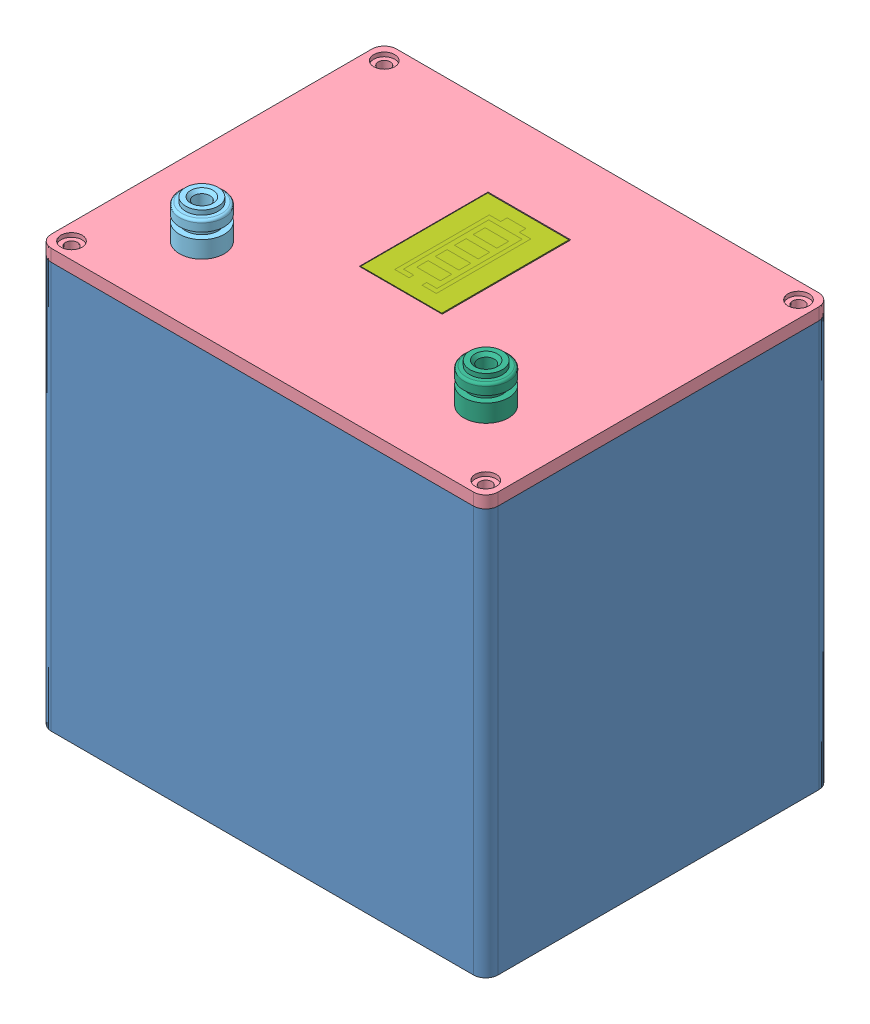
SolidWorks assembly BATTERY_ASSEM, configuration Default. Lengths in mm.
Overall size (110 112.56 85).
7 component instances, 7 part files, 9 mates.
Components (placement in the parent):
- Body-2: Body [Default] at (-59.4434 65 40.4582) size (110 100 85)
- Plate-2: Plate [Default] at (-9.4439 141 3.0418) size (99.4 2 74.4)
- ESP32_WROOM_32D-1: ESP32_WROOM_32D [Default] at (-26.4896 143.4115 23.6321) x (1 0 0) z (0 1 0) size (55 40 12.25)
- Cover-1: Cover [Default] at (-64.4434 160 45.4582) size (110 5.5 85)
- 4mm Black Banana Female Socket Jack Mount Connectors-1: 4mm Black Banana Female Socket Jack Mount Connectors [Default] at (-44.4434 172.4214 25.3582) x (0.999999 0 -0.001164) z (0 -1 0) size (11 17.07 15.05)
- 4mm Red Banana Female Socket Jack Mount Connectors-1: 4mm Red Banana Female Socket Jack Mount Connectors [Default] at (25.5566 172.564 25.3582) x (0.995817 0 -0.09137) z (0 -1 0) size (11 17.07 15.05)
- Lithium Battery Capacity Indicator Module-1: Lithium Battery Capacity Indicator Module [Default] at (-9.4973 157 -4.4242) x (1 0 0) z (0 1 0) size (20 43.5 8)
Mates (geometry in assembly coordinates):
- Coincident1: coincident anti-aligned: plane of Body-2 through (-59.4434 138.5 40.4582) normal (0 -1 0); plane of Plate-1 through (-9.2659 138.5 0.3116) normal (0 1 0)
- Coincident2: coincident anti-aligned: plane of Body-2 through (-59.4434 141 40.4582) normal (0 1 0); plane of Plate-2 through (-9.4439 141 3.0418) normal (0 -1 0)
- Coincident3: coincident anti-aligned: plane of Plate-2 through (-9.4439 143 3.0418) normal (0 1 0); plane of ESP32_WROOM_32D-1 through (1.7713 143 3.1863) normal (0 -1 0)
- Coincident4: coincident anti-aligned: plane of Body-2 through (-59.4434 160 40.4582) normal (0 1 0); plane of Cover-1 through (-64.4434 160 45.4582) normal (0 -1 0)
- Concentric1: concentric aligned: cylinder of Cover-1 through (-44.4434 163.001 25.3582) axis (0 -1 0) radius 3; cylinder of 4mm Black Banana Female Socket Jack Mount Connectors-1 through (-44.4434 172.4214 25.3582) axis (0 -1 0) radius 2
- Concentric2: concentric aligned: cylinder of Cover-1 through (25.5566 163.001 25.3582) axis (0 -1 0) radius 3; cylinder of 4mm Red Banana Female Socket Jack Mount Connectors-1 through (25.5566 172.564 25.3582) axis (0 -1 0) radius 2
- Coincident5: coincident aligned: plane of Body-2 through (45.5566 160 40.4582) normal (1 0 0); plane of Cover-1 through (45.5566 163 45.4582) normal (1 0 0)
- Coincident6: coincident aligned: plane of Body-2 through (-59.4434 160 45.4582) normal (0 0 1); plane of Cover-1 through (-64.4434 163 45.4582) normal (0 0 1)
- Coincident7: coincident aligned: plane of Cover-1 through (-64.4434 163 45.4582) normal (0 1 0); plane of Lithium Battery Capacity Indicator Module-1 through (-9.4973 163 -4.4242) normal (0 1 0)
